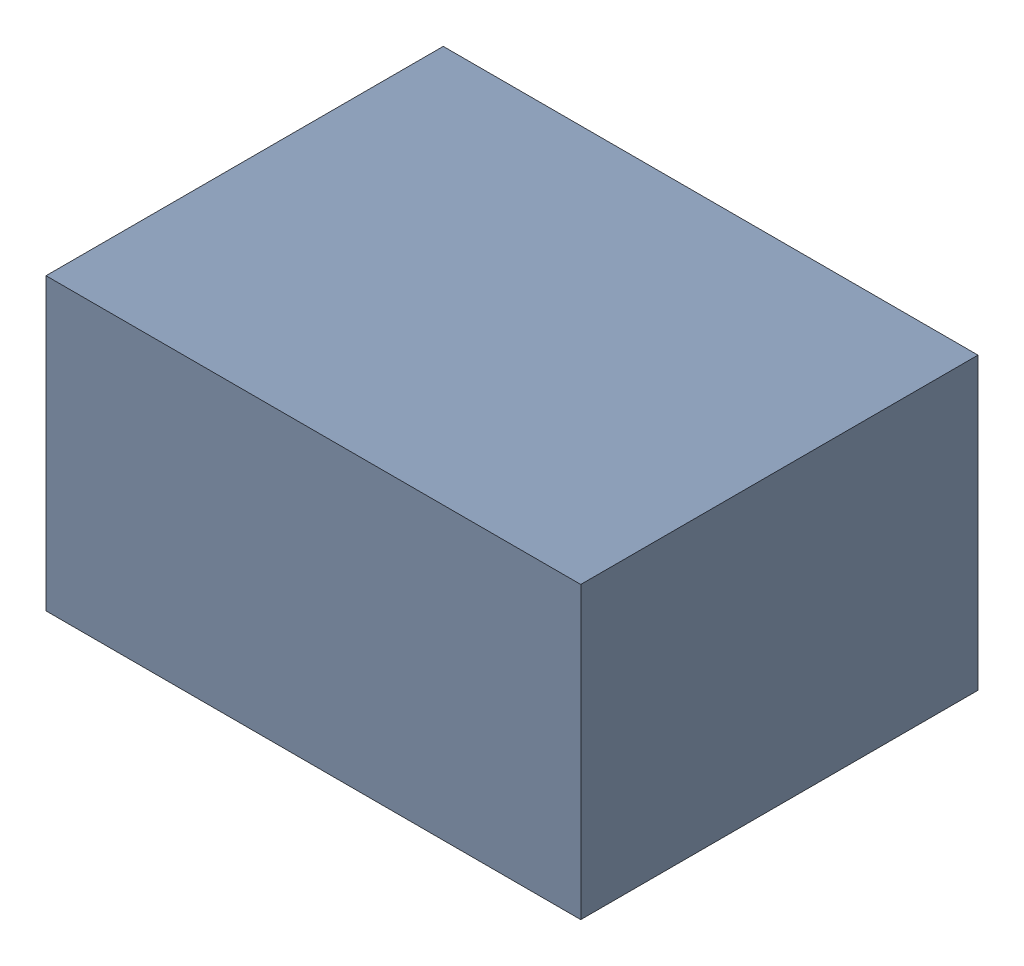
SolidWorks assembly C1, configuration Default. Lengths in mm.
Overall size (1.75 0.95 1.3).
2 component instances, 1 part files, 0 mates.
Components (placement in the parent):
- 580487056-1: 580487056 [Default] at (210.82 110.744 0) size (1.75 0.95 1.3)
  - Extruded_7-1: Extruded_7 [Default] at origin size (1.75 0.95 1.3)
